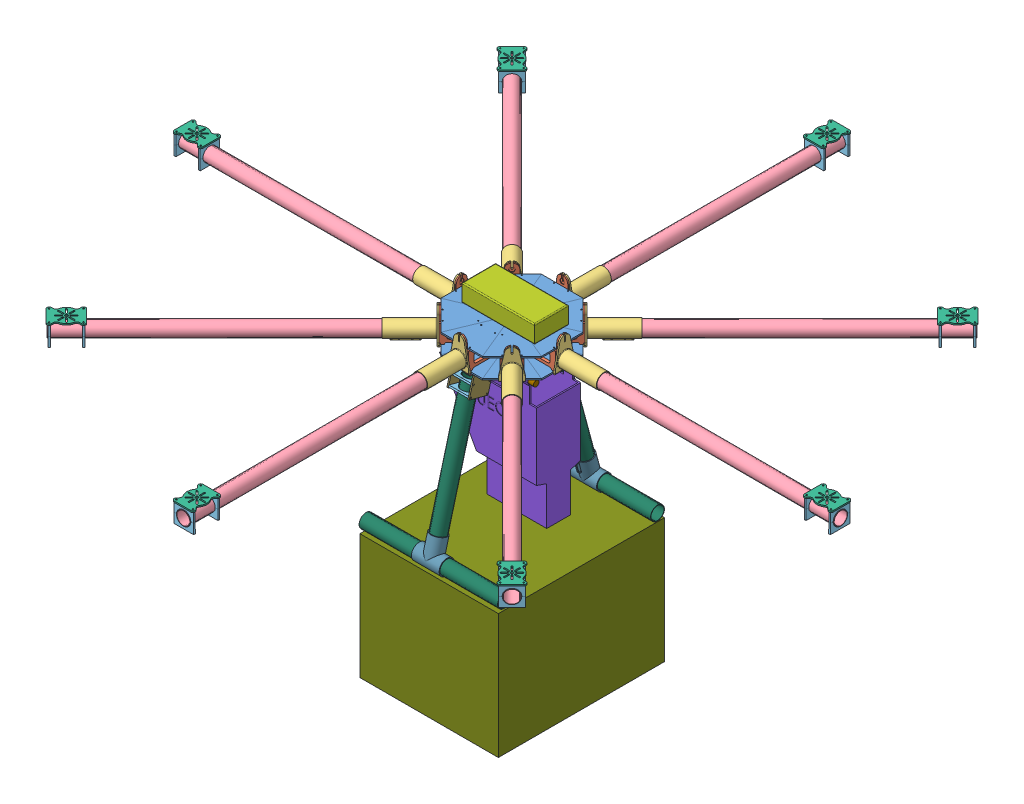
SolidWorks assembly ArmPositionFullAssembly, configuration Default. Lengths in mm.
Overall size (2379.25 1174.83 2379.25).
161 component instances, 18 part files, 28 mates.
Components (placement in the parent):
- ArmPosition-1: ArmPosition [Default] at (296.7598 860.8329 482.0953) size (150.36 112.06 1189.62)
  - NewHubPiece-1: NewHubPiece [Default] at (84.0761 108.6958 210.2555) size (150.36 5 181.5)
  - 50mmHingeToBase-1: 50mmHingeToBase [Default] at (84.0761 143.6958 240.2555) size (60 109.55 110)
  - NewHubPiece-2: NewHubPiece [Default] at (84.0761 178.6958 210.2555) size (150.36 5 181.5)
  - 50mmArmAssembly-1: 50mmArmAssembly [Default] at (-28.9933 18.3519 140.7775) x (1 0 0) z (0 -0.001194 0.999999) size (76 110.85 1008)
    - 50mmHingeToArm-1: 50mmHingeToArm [Default] at (113.0694 125.4328 79.3641) size (70 110.85 150)
    - 50mmDiamDroneArm-1: 50mmDiamDroneArm [Default] at (113.0694 125.4328 79.3641) x (0.775778 0.631006 0) z (0 0 1) size (50 50 995)
    - 50mmTubeClamp-1: 50mmTubeClamp [Default] at (113.0694 125.4328 1064.3641) size (70 35.35 6)
    - 50mmTubeClamp-2: 50mmTubeClamp [Default] at (113.0694 125.4328 1064.3641) x (-1 0 0) z (0 0 1) size (70 35.35 6)
    - 50mmTubeClamp-3: 50mmTubeClamp [Default] at (113.0694 125.4328 976.3641) x (-1 0 0) z (0 0 1) size (70 35.35 6)
    - 50mmTubeClamp-4: 50mmTubeClamp [Default] at (113.0694 125.4328 976.3641) size (70 35.35 6)
    - 50mmMotorHolder-1: 50mmMotorHolder [Default] at (104.7598 160.7795 1001.9104) size (76 5 104)
- ArmPosition-2: ArmPosition [Default] at (341.7183 860.8329 431.0669) x (0.707107 0 0.707107) z (-0.707107 0 0.707107) size (150.36 112.06 1189.62)
  - NewHubPiece-1: NewHubPiece [Default] at (84.0761 108.6958 210.2555) size (150.36 5 181.5)
  - 50mmHingeToBase-1: 50mmHingeToBase [Default] at (84.0761 143.6958 240.2555) size (60 109.55 110)
  - NewHubPiece-2: NewHubPiece [Default] at (84.0761 178.6958 210.2555) size (150.36 5 181.5)
  - 50mmArmAssembly-1: 50mmArmAssembly [Default] at (-28.9933 18.3519 140.7775) x (1 0 0) z (0 -0.001194 0.999999) size (76 110.85 1008)
    - 50mmHingeToArm-1: 50mmHingeToArm [Default] at (113.0694 125.4328 79.3641) size (70 110.85 150)
    - 50mmDiamDroneArm-1: 50mmDiamDroneArm [Default] at (113.0694 125.4328 79.3641) x (0.775778 0.631006 0) z (0 0 1) size (50 50 995)
    - 50mmTubeClamp-1: 50mmTubeClamp [Default] at (113.0694 125.4328 1064.3641) size (70 35.35 6)
    - 50mmTubeClamp-2: 50mmTubeClamp [Default] at (113.0694 125.4328 1064.3641) x (-1 0 0) z (0 0 1) size (70 35.35 6)
    - 50mmTubeClamp-3: 50mmTubeClamp [Default] at (113.0694 125.4328 976.3641) x (-1 0 0) z (0 0 1) size (70 35.35 6)
    - 50mmTubeClamp-4: 50mmTubeClamp [Default] at (113.0694 125.4328 976.3641) size (70 35.35 6)
    - 50mmMotorHolder-1: 50mmMotorHolder [Default] at (104.7598 160.7795 1001.9104) size (76 5 104)
- ArmPosition-3: ArmPosition [Default] at (460.6198 860.8329 471.7333) x (-0.707107 0 0.707107) z (-0.707107 0 -0.707107) size (150.36 112.06 1189.62)
  - NewHubPiece-1: NewHubPiece [Default] at (84.0761 108.6958 210.2555) size (150.36 5 181.5)
  - 50mmHingeToBase-1: 50mmHingeToBase [Default] at (84.0761 143.6958 240.2555) size (60 109.55 110)
  - NewHubPiece-2: NewHubPiece [Default] at (84.0761 178.6958 210.2555) size (150.36 5 181.5)
  - 50mmArmAssembly-1: 50mmArmAssembly [Default] at (-28.9933 18.3519 140.7775) x (1 0 0) z (0 -0.001194 0.999999) size (76 110.85 1008)
    - 50mmHingeToArm-1: 50mmHingeToArm [Default] at (113.0694 125.4328 79.3641) size (70 110.85 150)
    - 50mmDiamDroneArm-1: 50mmDiamDroneArm [Default] at (113.0694 125.4328 79.3641) x (0.775778 0.631006 0) z (0 0 1) size (50 50 995)
    - 50mmTubeClamp-1: 50mmTubeClamp [Default] at (113.0694 125.4328 1064.3641) size (70 35.35 6)
    - 50mmTubeClamp-2: 50mmTubeClamp [Default] at (113.0694 125.4328 1064.3641) x (-1 0 0) z (0 0 1) size (70 35.35 6)
    - 50mmTubeClamp-3: 50mmTubeClamp [Default] at (113.0694 125.4328 976.3641) x (-1 0 0) z (0 0 1) size (70 35.35 6)
    - 50mmTubeClamp-4: 50mmTubeClamp [Default] at (113.0694 125.4328 976.3641) size (70 35.35 6)
    - 50mmMotorHolder-1: 50mmMotorHolder [Default] at (104.7598 160.7795 1001.9104) size (76 5 104)
- ArmPosition-4: ArmPosition [Default] at (409.5914 860.8329 426.7748) x (0 0 1) z (-1 0 0) size (150.36 112.06 1189.62)
  - NewHubPiece-1: NewHubPiece [Default] at (84.0761 108.6958 210.2555) size (150.36 5 181.5)
  - 50mmHingeToBase-1: 50mmHingeToBase [Default] at (84.0761 143.6958 240.2555) size (60 109.55 110)
  - NewHubPiece-2: NewHubPiece [Default] at (84.0761 178.6958 210.2555) size (150.36 5 181.5)
  - 50mmArmAssembly-1: 50mmArmAssembly [Default] at (-28.9933 18.3519 140.7775) x (1 0 0) z (0 -0.001194 0.999999) size (76 110.85 1008)
    - 50mmHingeToArm-1: 50mmHingeToArm [Default] at (113.0694 125.4328 79.3641) size (70 110.85 150)
    - 50mmDiamDroneArm-1: 50mmDiamDroneArm [Default] at (113.0694 125.4328 79.3641) x (0.775778 0.631006 0) z (0 0 1) size (50 50 995)
    - 50mmTubeClamp-1: 50mmTubeClamp [Default] at (113.0694 125.4328 1064.3641) size (70 35.35 6)
    - 50mmTubeClamp-2: 50mmTubeClamp [Default] at (113.0694 125.4328 1064.3641) x (-1 0 0) z (0 0 1) size (70 35.35 6)
    - 50mmTubeClamp-3: 50mmTubeClamp [Default] at (113.0694 125.4328 976.3641) x (-1 0 0) z (0 0 1) size (70 35.35 6)
    - 50mmTubeClamp-4: 50mmTubeClamp [Default] at (113.0694 125.4328 976.3641) size (70 35.35 6)
    - 50mmMotorHolder-1: 50mmMotorHolder [Default] at (104.7598 160.7795 1001.9104) size (76 5 104)
- ArmPosition-5: ArmPosition [Default] at (419.9534 860.8329 590.6348) x (-0.707107 0 -0.707107) z (0.707107 0 -0.707107) size (150.36 112.06 1189.62)
  - NewHubPiece-1: NewHubPiece [Default] at (84.0761 108.6958 210.2555) size (150.36 5 181.5)
  - 50mmHingeToBase-1: 50mmHingeToBase [Default] at (84.0761 143.6958 240.2555) size (60 109.55 110)
  - NewHubPiece-2: NewHubPiece [Default] at (84.0761 178.6958 210.2555) size (150.36 5 181.5)
  - 50mmArmAssembly-1: 50mmArmAssembly [Default] at (-28.9933 18.3519 140.7775) x (1 0 0) z (0 -0.001194 0.999999) size (76 110.85 1008)
    - 50mmHingeToArm-1: 50mmHingeToArm [Default] at (113.0694 125.4328 79.3641) size (70 110.85 150)
    - 50mmDiamDroneArm-1: 50mmDiamDroneArm [Default] at (113.0694 125.4328 79.3641) x (0.775778 0.631006 0) z (0 0 1) size (50 50 995)
    - 50mmTubeClamp-1: 50mmTubeClamp [Default] at (113.0694 125.4328 1064.3641) size (70 35.35 6)
    - 50mmTubeClamp-2: 50mmTubeClamp [Default] at (113.0694 125.4328 1064.3641) x (-1 0 0) z (0 0 1) size (70 35.35 6)
    - 50mmTubeClamp-3: 50mmTubeClamp [Default] at (113.0694 125.4328 976.3641) x (-1 0 0) z (0 0 1) size (70 35.35 6)
    - 50mmTubeClamp-4: 50mmTubeClamp [Default] at (113.0694 125.4328 976.3641) size (70 35.35 6)
    - 50mmMotorHolder-1: 50mmMotorHolder [Default] at (104.7598 160.7795 1001.9104) size (76 5 104)
- ArmPosition-6: ArmPosition [Default] at (301.0519 860.8329 549.9684) x (0.707107 0 -0.707107) z (0.707107 0 0.707107) size (150.36 112.06 1189.62)
  - NewHubPiece-1: NewHubPiece [Default] at (84.0761 108.6958 210.2555) size (150.36 5 181.5)
  - 50mmHingeToBase-1: 50mmHingeToBase [Default] at (84.0761 143.6958 240.2555) size (60 109.55 110)
  - NewHubPiece-2: NewHubPiece [Default] at (84.0761 178.6958 210.2555) size (150.36 5 181.5)
  - 50mmArmAssembly-1: 50mmArmAssembly [Default] at (-28.9933 18.3519 140.7775) x (1 0 0) z (0 -0.001194 0.999999) size (76 110.85 1008)
    - 50mmHingeToArm-1: 50mmHingeToArm [Default] at (113.0694 125.4328 79.3641) size (70 110.85 150)
    - 50mmDiamDroneArm-1: 50mmDiamDroneArm [Default] at (113.0694 125.4328 79.3641) x (0.775778 0.631006 0) z (0 0 1) size (50 50 995)
    - 50mmTubeClamp-1: 50mmTubeClamp [Default] at (113.0694 125.4328 1064.3641) size (70 35.35 6)
    - 50mmTubeClamp-2: 50mmTubeClamp [Default] at (113.0694 125.4328 1064.3641) x (-1 0 0) z (0 0 1) size (70 35.35 6)
    - 50mmTubeClamp-3: 50mmTubeClamp [Default] at (113.0694 125.4328 976.3641) x (-1 0 0) z (0 0 1) size (70 35.35 6)
    - 50mmTubeClamp-4: 50mmTubeClamp [Default] at (113.0694 125.4328 976.3641) size (70 35.35 6)
    - 50mmMotorHolder-1: 50mmMotorHolder [Default] at (104.7598 160.7795 1001.9104) size (76 5 104)
- ArmPosition-7: ArmPosition [Default] at (352.0803 860.8329 594.9269) x (0 0 -1) z (1 0 0) size (150.36 112.06 1189.62)
  - NewHubPiece-1: NewHubPiece [Default] at (84.0761 108.6958 210.2555) size (150.36 5 181.5)
  - 50mmHingeToBase-1: 50mmHingeToBase [Default] at (84.0761 143.6958 240.2555) size (60 109.55 110)
  - NewHubPiece-2: NewHubPiece [Default] at (84.0761 178.6958 210.2555) size (150.36 5 181.5)
  - 50mmArmAssembly-1: 50mmArmAssembly [Default] at (-28.9933 18.3519 140.7775) x (1 0 0) z (0 -0.001194 0.999999) size (76 110.85 1008)
    - 50mmHingeToArm-1: 50mmHingeToArm [Default] at (113.0694 125.4328 79.3641) size (70 110.85 150)
    - 50mmDiamDroneArm-1: 50mmDiamDroneArm [Default] at (113.0694 125.4328 79.3641) x (0.775778 0.631006 0) z (0 0 1) size (50 50 995)
    - 50mmTubeClamp-1: 50mmTubeClamp [Default] at (113.0694 125.4328 1064.3641) size (70 35.35 6)
    - 50mmTubeClamp-2: 50mmTubeClamp [Default] at (113.0694 125.4328 1064.3641) x (-1 0 0) z (0 0 1) size (70 35.35 6)
    - 50mmTubeClamp-3: 50mmTubeClamp [Default] at (113.0694 125.4328 976.3641) x (-1 0 0) z (0 0 1) size (70 35.35 6)
    - 50mmTubeClamp-4: 50mmTubeClamp [Default] at (113.0694 125.4328 976.3641) size (70 35.35 6)
    - 50mmMotorHolder-1: 50mmMotorHolder [Default] at (104.7598 160.7795 1001.9104) size (76 5 104)
- ArmPosition-8: ArmPosition [Default] at (464.9119 860.8329 539.6064) x (-1 0 0) z (0 0 -1) size (150.36 112.06 1189.62)
  - NewHubPiece-1: NewHubPiece [Default] at (84.0761 108.6958 210.2555) size (150.36 5 181.5)
  - 50mmHingeToBase-1: 50mmHingeToBase [Default] at (84.0761 143.6958 240.2555) size (60 109.55 110)
  - NewHubPiece-2: NewHubPiece [Default] at (84.0761 178.6958 210.2555) size (150.36 5 181.5)
  - 50mmArmAssembly-1: 50mmArmAssembly [Default] at (-28.9933 18.3519 140.7775) x (1 0 0) z (0 -0.001194 0.999999) size (76 110.85 1008)
    - 50mmHingeToArm-1: 50mmHingeToArm [Default] at (113.0694 125.4328 79.3641) size (70 110.85 150)
    - 50mmDiamDroneArm-1: 50mmDiamDroneArm [Default] at (113.0694 125.4328 79.3641) x (0.775778 0.631006 0) z (0 0 1) size (50 50 995)
    - 50mmTubeClamp-1: 50mmTubeClamp [Default] at (113.0694 125.4328 1064.3641) size (70 35.35 6)
    - 50mmTubeClamp-2: 50mmTubeClamp [Default] at (113.0694 125.4328 1064.3641) x (-1 0 0) z (0 0 1) size (70 35.35 6)
    - 50mmTubeClamp-3: 50mmTubeClamp [Default] at (113.0694 125.4328 976.3641) x (-1 0 0) z (0 0 1) size (70 35.35 6)
    - 50mmTubeClamp-4: 50mmTubeClamp [Default] at (113.0694 125.4328 976.3641) size (70 35.35 6)
    - 50mmMotorHolder-1: 50mmMotorHolder [Default] at (104.7598 160.7795 1001.9104) size (76 5 104)
- Battery-1: Battery [Default] at (251.4391 1044.5287 562.6978) size (263 64 122)
- BallBucketAssembly-1: BallBucketAssembly [Default] at (78.9066 432.3289 69.7367) size (365.59 486.4 197)
  - BallBucket-1: BallBucket [Default] at (253.8455 203.81 361.249) size (356.65 480.38 173)
  - BucketRod-1: BucketRod [Default] at (249.5569 203.81 208.249) size (294.29 20 20)
  - BucketLiquidCylinder-1: BucketLiquidCylinder [Default] at (222.6999 186.6383 360.2693) x (0.928619 -0.039355 -0.368943) z (0.368943 0.20341 0.906921) size (141.61 217.05 36)
  - BucketRodSupport-1: BucketRodSupport [Default] at (253.8455 203.81 208.249) size (20 28.65 44)
  - BucketRodSupport-2: BucketRodSupport [Default] at (253.8455 203.81 361.249) size (20 28.65 44)
  - BucketRodSupport-3: BucketRodSupport [Default] at (437.9168 203.81 361.249) size (20 28.65 44)
  - BucketRodSupport-4: BucketRodSupport [Default] at (437.9168 203.81 208.249) size (20 28.65 44)
  - BucketRod-2: BucketRod [Default] at (249.5569 169.1219 479.6191) x (1 0 0) z (0 0.345477 0.938427) size (294.29 20 20)
- DroneLegAssembly-1: DroneLegAssembly [Default] at (279.311 970.5444 324.7978) x (0 0 1) z (1 0 0) size (228.54 591.89 500)
  - DroneLegHolder-1: DroneLegHolder [Default] at (24.5531 1.0156 69.8023) size (87.27 101.47 5)
  - 50mmTubeClamp-1: 50mmTubeClamp [Default] at (47.7584 47.4978 110.1489) x (0.965926 0.258819 0) z (-0.258819 0.965926 0) size (70 35.35 6)
  - 50mmTubeClamp-2: 50mmTubeClamp [Default] at (35.6425 92.7146 110.1489) x (-0.965926 -0.258819 0) z (0.258819 -0.965926 0) size (70 35.35 6)
  - 50mmTubeClamp-3: 50mmTubeClamp [Default] at (35.6425 92.7146 110.1489) x (0.965926 0.258819 0) z (0.258819 -0.965926 0) size (70 35.35 6)
  - 50mmTubeClamp-4: 50mmTubeClamp [Default] at (45.1702 57.157 110.1489) x (0.965926 0.258819 0) z (0.258819 -0.965926 0) size (70 35.35 6)
  - DroneLegHolder-2: DroneLegHolder [Default] at (24.5531 1.0156 145.4956) size (87.27 101.47 5)
  - 50mmDroneLegToBase-1: 50mmDroneLegToBase [Default] at (47.7381 1.0156 73.7515) x (0 0 1) z (-1 0 0) size (20 10 100)
  - 50mmDroneLegToBase-2: 50mmDroneLegToBase [Default] at (61.3681 1.0156 146.5463) x (0 0 -1) z (1 0 0) size (20 10 100)
  - New50mmBottomJoint-1: New50mmBottomJoint [Default] at (-88.6393 556.5407 160.1489) x (0.965926 0.258819 0) z (0 0 -1) size (64 103 100)
  - Short50mmDroneLeg-1: Short50mmDroneLeg [Default] at (47.2407 49.4296 110.1489) x (0.779439 0.20885 -0.590641) z (-0.258819 0.965926 0) size (50 50 500)
  - Short50mmDroneLeg-2: Short50mmDroneLeg [Default] at (-88.6393 556.5407 -147.8451) x (0.716049 -0.69805 0) z (0 0 1) size (50 50 500)
- DroneLegAssembly-2: DroneLegAssembly [Default] at (480.6554 970.5444 696.904) x (0 0 -1) z (-1 0 0) size (228.54 591.89 500)
  - DroneLegHolder-1: DroneLegHolder [Default] at (24.5531 1.0156 69.8023) size (87.27 101.47 5)
  - 50mmTubeClamp-1: 50mmTubeClamp [Default] at (47.7584 47.4978 110.1489) x (0.965926 0.258819 0) z (-0.258819 0.965926 0) size (70 35.35 6)
  - 50mmTubeClamp-2: 50mmTubeClamp [Default] at (35.6425 92.7146 110.1489) x (-0.965926 -0.258819 0) z (0.258819 -0.965926 0) size (70 35.35 6)
  - 50mmTubeClamp-3: 50mmTubeClamp [Default] at (35.6425 92.7146 110.1489) x (0.965926 0.258819 0) z (0.258819 -0.965926 0) size (70 35.35 6)
  - 50mmTubeClamp-4: 50mmTubeClamp [Default] at (45.1702 57.157 110.1489) x (0.965926 0.258819 0) z (0.258819 -0.965926 0) size (70 35.35 6)
  - DroneLegHolder-2: DroneLegHolder [Default] at (24.5531 1.0156 145.4956) size (87.27 101.47 5)
  - 50mmDroneLegToBase-1: 50mmDroneLegToBase [Default] at (47.7381 1.0156 73.7515) x (0 0 1) z (-1 0 0) size (20 10 100)
  - 50mmDroneLegToBase-2: 50mmDroneLegToBase [Default] at (61.3681 1.0156 146.5463) x (0 0 -1) z (1 0 0) size (20 10 100)
  - New50mmBottomJoint-1: New50mmBottomJoint [Default] at (-88.6393 556.5407 160.1489) x (0.965926 0.258819 0) z (0 0 -1) size (64 103 100)
  - Short50mmDroneLeg-1: Short50mmDroneLeg [Default] at (47.2407 49.4296 110.1489) x (0.779439 0.20885 -0.590641) z (-0.258819 0.965926 0) size (50 50 500)
  - Short50mmDroneLeg-2: Short50mmDroneLeg [Default] at (-88.6393 556.5407 -147.8451) x (0.716049 -0.69805 0) z (0 0 1) size (50 50 500)
- StorageBox-1: StorageBox [Default] at (184.3757 -167.9984 40.494) size (500 450 600)
  - BaseBlock-1: BaseBlock [Default] at (-55.9599 101.6948 767.1143) size (500 450 600)
  - CupStorage-1: CupStorage [Default] at (882.1946 34.1249 161.3658) x (0.007369 0 0.999973) z (-0.999973 0 0.007369) size (536.8 119.37 182.42)
    - SoloCup-1: SoloCup [Default] at (135.563 292.5699 600.2365) size (96.65 119.37 96.65)
    - SoloCup-2: SoloCup [Default] at (477.5943 292.5699 516.5315) size (96.65 119.37 96.65)
    - SoloCup-3: SoloCup [Default] at (86.5797 292.5699 517.1338) size (96.65 119.37 96.65)
    - SoloCup-4: SoloCup [Default] at (429.6882 292.5699 602.3039) size (96.65 119.37 96.65)
    - SoloCup-5: SoloCup [Default] at (380.7513 292.5699 517.5282) size (96.65 119.37 96.65)
    - SoloCup-6: SoloCup [Default] at (283.0336 292.5699 517.7873) size (96.65 119.37 96.65)
    - SoloCup-7: SoloCup [Default] at (526.7308 292.5699 600.3394) size (96.65 119.37 96.65)
    - SoloCup-8: SoloCup [Default] at (234.2027 292.5699 600.9501) size (96.65 119.37 96.65)
    - SoloCup-9: SoloCup [Default] at (332.0914 292.5699 601.2137) size (96.65 119.37 96.65)
    - SoloCup-10: SoloCup [Default] at (185.2343 292.5699 517.3586) size (96.65 119.37 96.65)
    - PingPongBall-1: PingPongBall [Default] at (278.3478 273.1207 518.1565) size (38 38 38)
  - CupStorage-2: CupStorage [Default] at (709.7631 34.1249 159.2975) x (0.01289 0 0.999917) z (-0.999917 0 0.01289) size (536.8 119.37 182.42)
    - SoloCup-1: SoloCup [Default] at (135.563 292.5699 600.2365) size (96.65 119.37 96.65)
    - SoloCup-2: SoloCup [Default] at (477.5943 292.5699 516.5315) size (96.65 119.37 96.65)
    - SoloCup-3: SoloCup [Default] at (86.5797 292.5699 517.1338) size (96.65 119.37 96.65)
    - SoloCup-4: SoloCup [Default] at (429.6882 292.5699 602.3039) size (96.65 119.37 96.65)
    - SoloCup-5: SoloCup [Default] at (380.7513 292.5699 517.5282) size (96.65 119.37 96.65)
    - SoloCup-6: SoloCup [Default] at (283.0336 292.5699 517.7873) size (96.65 119.37 96.65)
    - SoloCup-7: SoloCup [Default] at (526.7308 292.5699 600.3394) size (96.65 119.37 96.65)
    - SoloCup-8: SoloCup [Default] at (234.2027 292.5699 600.9501) size (96.65 119.37 96.65)
    - SoloCup-9: SoloCup [Default] at (332.0914 292.5699 601.2137) size (96.65 119.37 96.65)
    - SoloCup-10: SoloCup [Default] at (185.2343 292.5699 517.3586) size (96.65 119.37 96.65)
    - PingPongBall-1: PingPongBall [Default] at (278.3478 273.1207 518.1565) size (38 38 38)
  - Battery-1: Battery [Default] at (12.3576 126.6948 331.0042) size (263 64 122)
  - Battery-2: Battery [Default] at (12.3576 126.6948 465.7618) size (263 64 122)
  - Battery-3: Battery [Default] at (12.3576 126.6948 605.2903) size (263 64 122)
  - Battery-4: Battery [Default] at (12.3576 126.6948 733.3395) size (263 64 122)
  - Battery-5: Battery [Default] at (12.3576 190.6948 540.1787) size (263 64 122)
Mates (geometry in assembly coordinates):
- Coincident1: coincident aligned: plane of ArmPosition-1/NewHubPiece-2 through (380.8358 1044.5287 692.3509) normal (0 1 0); plane of ArmPosition-2/NewHubPiece-2 through (252.496 1044.5287 639.1907) normal (0 1 0)
- Coincident3: coincident anti-aligned: plane of ArmPosition-1/NewHubPiece-2 through (316.6659 1044.5287 665.7708) normal (-0.92388 0 -0.382683); plane of ArmPosition-2/NewHubPiece-2 through (316.6659 1044.5287 665.7708) normal (0.92388 0 0.382683)
- Coincident4: coincident aligned: line of ArmPosition-1/NewHubPiece-2 through (380.8358 1044.5287 510.8509) axis (0 -1 0); line of ArmPosition-2/NewHubPiece-2 through (380.8358 1044.5287 510.8509) axis (0 -1 0)
- Coincident5: coincident aligned: plane of ArmPosition-3/NewHubPiece-2 through (252.496 1044.5287 382.511) normal (0 1 0); plane of ArmPosition-4/NewHubPiece-2 through (199.3358 1044.5287 510.8509) normal (0 1 0)
- Coincident6: coincident anti-aligned: plane of ArmPosition-3/NewHubPiece-2 through (225.9159 1044.5287 446.6809) normal (-0.382683 0 0.92388); plane of ArmPosition-4/NewHubPiece-2 through (225.9159 1044.5287 446.6809) normal (0.382683 0 -0.92388)
- Coincident7: coincident aligned: line of ArmPosition-3/NewHubPiece-2 through (380.8358 1044.5287 510.8509) axis (0 -1 0); line of ArmPosition-4/NewHubPiece-2 through (380.8358 1044.5287 510.8509) axis (0 -1 0)
- Coincident8: coincident anti-aligned: plane of ArmPosition-2/NewHubPiece-2 through (225.9159 1044.5287 575.0208) normal (-0.382683 0 -0.92388); plane of ArmPosition-4/NewHubPiece-2 through (225.9159 1044.5287 575.0208) normal (0.382683 0 0.92388)
- Coincident9: coincident aligned: plane of ArmPosition-2/NewHubPiece-2 through (252.496 1044.5287 639.1907) normal (0 1 0); plane of ArmPosition-4/NewHubPiece-2 through (199.3358 1044.5287 510.8509) normal (0 1 0)
- Coincident10: coincident aligned: line of ArmPosition-2/NewHubPiece-2 through (380.8358 1044.5287 510.8509) axis (0 -1 0); line of ArmPosition-3/NewHubPiece-2 through (380.8358 1044.5287 510.8509) axis (0 -1 0)
- Coincident11: coincident aligned: line of ArmPosition-6/NewHubPiece-2 through (380.8358 1044.5287 510.8509) axis (0 -1 0); line of ArmPosition-7/NewHubPiece-2 through (380.8358 1044.5287 510.8509) axis (0 -1 0)
- Coincident12: coincident aligned: plane of ArmPosition-5/NewHubPiece-2 through (509.1757 1044.5287 382.511) normal (0 1 0); plane of ArmPosition-7/NewHubPiece-2 through (562.3358 1044.5287 510.8509) normal (0 1 0)
- Coincident13: coincident anti-aligned: plane of ArmPosition-5/NewHubPiece-2 through (535.7558 1044.5287 446.6809) normal (0.382683 0 0.92388); plane of ArmPosition-7/NewHubPiece-2 through (535.7558 1044.5287 446.6809) normal (-0.382683 0 -0.92388)
- Coincident14: coincident aligned: line of ArmPosition-5/NewHubPiece-2 through (380.8358 1044.5287 510.8509) axis (0 -1 0); line of ArmPosition-6/NewHubPiece-2 through (380.8358 1044.5287 510.8509) axis (0 -1 0)
- Coincident15: coincident aligned: plane of ArmPosition-5/NewHubPiece-2 through (509.1757 1044.5287 382.511) normal (0 1 0); plane of ArmPosition-8/NewHubPiece-2 through (380.8358 1044.5287 329.3509) normal (0 1 0)
- Coincident16: coincident anti-aligned: plane of ArmPosition-6/NewHubPiece-2 through (535.7558 1044.5287 575.0208) normal (0.382683 0 -0.92388); plane of ArmPosition-7/NewHubPiece-2 through (535.7558 1044.5287 575.0208) normal (-0.382683 0 0.92388)
- Coincident17: coincident anti-aligned: plane of ArmPosition-5/NewHubPiece-2 through (445.0058 1044.5287 355.9309) normal (-0.92388 0 -0.382683); plane of ArmPosition-8/NewHubPiece-2 through (445.0058 1044.5287 355.9309) normal (0.92388 0 0.382683)
- Coincident18: coincident aligned: line of ArmPosition-5/NewHubPiece-2 through (380.8358 1044.5287 510.8509) axis (0 -1 0); line of ArmPosition-8/NewHubPiece-2 through (380.8358 1044.5287 510.8509) axis (0 -1 0)
- Coincident19: coincident aligned: plane of ArmPosition-6/NewHubPiece-2 through (509.1757 1044.5287 639.1907) normal (0 1 0); plane of ArmPosition-7/NewHubPiece-2 through (562.3358 1044.5287 510.8509) normal (0 1 0)
- Coincident20: coincident aligned: plane of ArmPosition-2/NewHubPiece-2 through (252.496 1044.5287 639.1907) normal (0 1 0); plane of ArmPosition-7/NewHubPiece-2 through (562.3358 1044.5287 510.8509) normal (0 1 0)
- Coincident21: coincident aligned: line of ArmPosition-3/NewHubPiece-2 through (380.8358 1044.5287 510.8509) axis (0 -1 0); line of ArmPosition-5/NewHubPiece-2 through (380.8358 1044.5287 510.8509) axis (0 -1 0)
- Coincident22: coincident anti-aligned: plane of ArmPosition-1/NewHubPiece-2 through (445.0058 1044.5287 665.7708) normal (0.92388 0 -0.382683); plane of ArmPosition-6/NewHubPiece-2 through (445.0058 1044.5287 665.7708) normal (-0.92388 0 0.382683)
- Coincident23: coincident anti-aligned: plane of ArmPosition-5/NewHubPiece-2 through (509.1757 1044.5287 382.511) normal (0 1 0); plane of Battery-1 through (251.4391 1044.5287 562.6978) normal (0 -1 0)
- Coincident24: coincident anti-aligned: plane of ArmPosition-5/NewHubPiece-1 through (509.1757 969.5287 382.511) normal (0 -1 0); plane of BallBucketAssembly-1/BucketRodSupport-3 through (708.9056 969.5287 430.9857) normal (0 1 0)
- Coincident25: coincident: plane of ArmPosition-4/NewHubPiece-1 through (199.3358 974.5287 510.8509) normal (-1 0 0); line of BallBucketAssembly-1/BallBucket-1 through (199.3358 878.1275 590.9857) axis (0 0 -1)
- Coincident26: coincident anti-aligned: plane of ArmPosition-5/NewHubPiece-1 through (509.1757 969.5287 382.511) normal (0 -1 0); plane of DroneLegAssembly-1/50mmDroneLegToBase-1 through (353.0625 969.5287 372.5359) normal (0 1 0)
- Coincident27: coincident anti-aligned: plane of ArmPosition-8/50mmHingeToBase-1 through (380.8358 1059.5287 329.3509) normal (0 0 1); plane of DroneLegAssembly-1/50mmDroneLegToBase-2 through (409.8066 959.5287 329.3509) normal (0 0 -1)
- Coincident29: coincident anti-aligned: plane of ArmPosition-1/NewHubPiece-1 through (380.8358 969.5287 692.3509) normal (0 -1 0); plane of DroneLegAssembly-2/50mmDroneLegToBase-1 through (406.9039 969.5287 649.1659) normal (0 1 0)
- Coincident30: coincident anti-aligned: plane of ArmPosition-1/50mmHingeToBase-1 through (380.8358 1059.5287 692.3509) normal (0 0 -1); plane of DroneLegAssembly-2/50mmDroneLegToBase-1 through (390.8532 959.5287 692.3509) normal (0 0 1)
